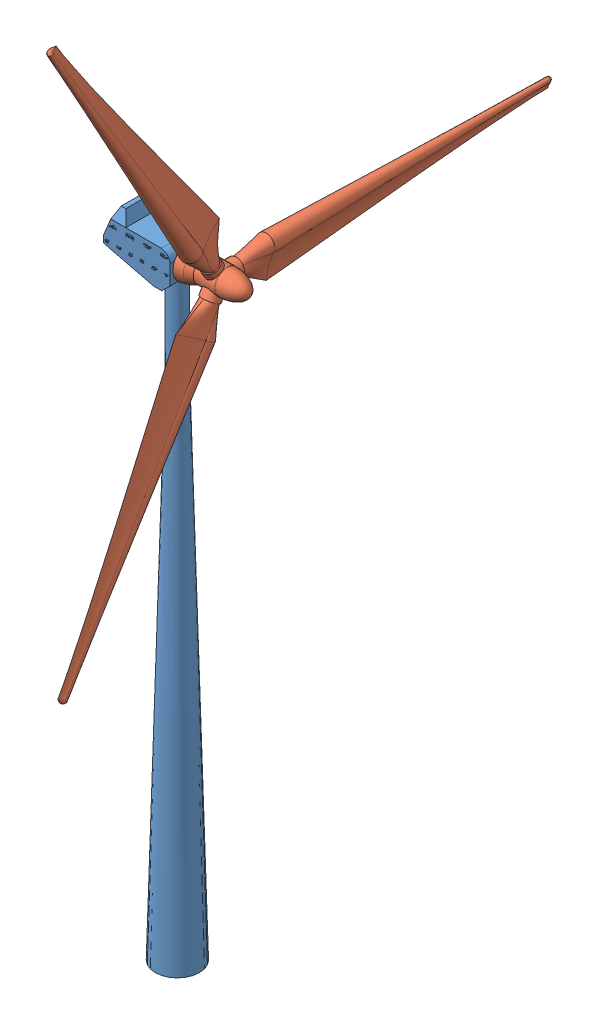
SolidWorks assembly Windmill FINAL, configuration Default. Lengths in mm.
Overall size (223.93 1589.12 893.49).
2 component instances, 2 part files, 2 mates.
Components (placement in the parent):
- base.windmill-1: base.windmill [Default] at (-55.7256 449.3916 39.1412) size (134.84 1135.14 78.22)
- Part2.Windmill-1: Part2.Windmill [Default] at (44.391 450.6422 -7.4652) x (0 0 -1) z (1 0 0) size (893.49 1017.45 106)
Mates (geometry in assembly coordinates):
- Coincident1: coincident: plane of base.windmill-1 through (-5.609 344.5407 109.1412) normal (1 0 0); plane of Part2.Windmill-1 through (-5.609 453.4743 73.6736) normal (-1 0 0)
- Lock1: lock: unknown of base.windmill-1; unknown of Part2.Windmill-1
